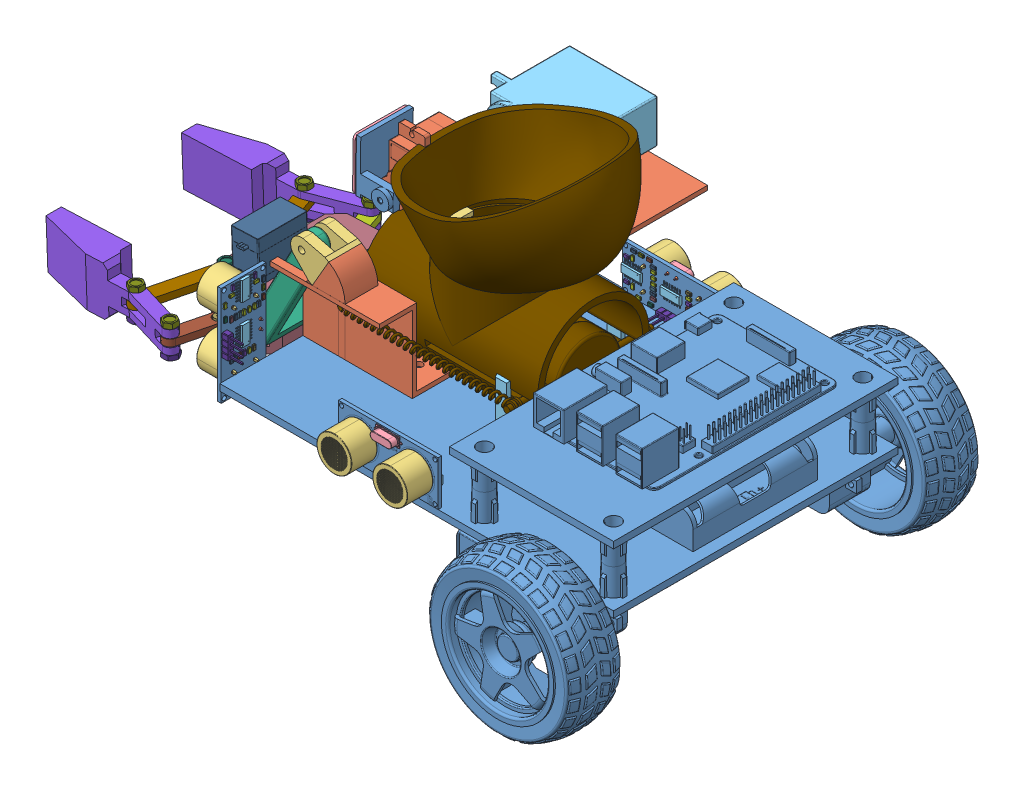
SolidWorks assembly Final1, configuration Default. Lengths in mm.
Overall size (322.81 176.18 188.6).
225 component instances, 41 part files, 17 mates.
Components (placement in the parent):
- body-final(18x13)-1: body-final(18x13) [Default] at (34.2506 -12.1128 3.3037) size (190.78 93.48 188.6)
- Assem3-1: Assem3 [Default] at (112.861 101.0924 210.176) x (0 0 -1) z (-1 0 0) size (142.46 166.43 202.05)
  - Base-1: Base [Default] at (127.5084 -19.7377 87.1974) size (130 49.99 70.01)
  - joint-1: joint [Default] at (35.8214 -26.2329 92.7019) x (0 -0.866025 -0.5) z (-1 0 0) size (15 15 15)
  - joint-half-1: joint-half [Default] at (97.1971 -26.2329 92.7019) x (0 0.866025 0.5) z (1 0 0) size (15 15 15)
  - Servo MG996R-1: Servo MG996R [Predeterminado] at (153.349 -21.2329 111.3621) x (0 0 -1) z (0 1 0) size (53.6 47.6 20)
  - arm1-1: arm1 [Default] at (128.0479 7.6553 52.8151) x (1 0 0) z (0 -0.885193 -0.465225) size (110.02 107.88 131.32)
    - arm-2: arm [Default] at (-24.8916 55.9585 30.1716) size (87 10 66.93)
    - Assembly 2.0 upload.stp-2: Assembly 2.0 upload.stp [Default] at (-62.3508 78.3564 -62.8111) x (0 -0.866025 0.5) z (-1 0 0) size (99.56 43.3 110.02)
      - gear.stp-1: gear.stp [Default] at (1.3043 -4.9957 -15) x (0.330984 0 0.943636) z (-0.943636 0 0.330984) size (53 3 32)
      - gripper.stp-1: gripper.stp [Default] at (-7.3079 -8.4957 47.6327) size (71 22 21.5)
      - tuas.stp-1: tuas.stp [Default] at (-30.3079 -1.9957 40.1327) x (-0.966894 0 -0.255178) z (-0.255178 0 0.966894) size (6.5 3 40.25)
      - gripper.stp-2: gripper.stp [Default] at (-9.8664 1.0043 -46.8477) x (1 0 0) z (0 0 -1) size (71 22 21.5)
      - tuas.stp-2: tuas.stp [Default] at (-32.8664 -1.9957 -39.3477) x (0.943636 0 -0.330984) z (-0.330984 0 -0.943636) size (6.5 3 40.25)
      - microservoSG90.stp-1: microservoSG90.stp [Default] at (1.3043 28.3043 9.9) x (0 0 -1) z (-1 0 0) size (32.3 29.8 12.41)
      - gear 2.1.stp-1: gear 2.1.stp [Default] at (1.3043 -1.9957 15) x (0.255178 0 -0.966894) z (-0.966894 0 -0.255178) size (52.85 3 31.7)
      - servo horn 1 v2.stp-1: servo horn 1 v2.stp [Default] at (1.3043 -1.4957 15) x (-0.966894 0 -0.255178) z (-0.255178 0 0.966894) size (7.2 3.7 21.2)
      - base 2.0 upload.stp-1: base 2.0 upload.stp [Default] at (28.3043 -7.9957 35) size (50 18.1 60)
      - Gear Ring.stp-1: Gear Ring.stp [Default] at (1.3043 -1.7957 -15) x (-0.620589 0 -0.784136) z (0.784136 0 -0.620589) size (18 2 18)
      - AS 1427 - M3 x 10.stp-1: AS 1427 - M3 x 10.stp [Default] at (1.3043 0.2043 -15) x (0 -1 0) z (0 0 1) size (12.33 5.5 6.35)
      - AS 1427 - M3 x 10.stp-2: AS 1427 - M3 x 10.stp [Default] at (-21.6957 -1.9957 -7.5) x (0 -1 0) z (0 0 1) size (12.33 5.5 6.35)
      - AS 1427 - M3 x 10.stp-3: AS 1427 - M3 x 10.stp [Default] at (-21.6957 -1.9957 7.5) x (0 -1 0) z (0 0 1) size (12.33 5.5 6.35)
      - AS 1427 - M3 x 12.stp-1: AS 1427 - M3 x 12.stp [Default] at (-9.8664 1.0043 -46.8477) x (0 -1 0) z (0 0 1) size (14.33 5.5 6.35)
      - AS 1427 - M3 x 12.stp-2: AS 1427 - M3 x 12.stp [Default] at (-32.8664 1.0043 -39.3477) x (0 -1 0) z (0 0 1) size (14.33 5.5 6.35)
      - AS 1427 - M3 x 12.stp-3: AS 1427 - M3 x 12.stp [Default] at (-7.3079 1.5043 47.6327) x (0 -1 0) z (0 0 1) size (14.33 5.5 6.35)
      - AS 1427 - M3 x 12.stp-4: AS 1427 - M3 x 12.stp [Default] at (-30.3079 1.5043 40.1327) x (0 -1 0) z (0 0 1) size (14.33 5.5 6.35)
      - AS 1112 - M3,5.stp-1: AS 1112 - M3,5.stp [Default] at (1.3043 -10.0957 -15) x (0 1 0) z (0 0 1) size (2.1 6.93 6)
      - AS 1112 - M3,5.stp-2: AS 1112 - M3,5.stp [Default] at (-21.6957 -10.0957 -7.5) x (0 1 0) z (0 0 1) size (2.1 6.93 6)
      - AS 1112 - M3,5.stp-3: AS 1112 - M3,5.stp [Default] at (-21.6957 -10.0957 7.5) x (0 1 0) z (0 0 1) size (2.1 6.93 6)
      - AS 1112 - M3,5.stp-4: AS 1112 - M3,5.stp [Default] at (-32.8664 -11.0957 -39.3477) x (0 1 0) z (0 0 1) size (2.1 6.93 6)
      - AS 1112 - M3,5.stp-5: AS 1112 - M3,5.stp [Default] at (-9.8664 -11.0957 -46.8477) x (0 1 0) z (0 0 1) size (2.1 6.93 6)
      - AS 1112 - M3,5.stp-6: AS 1112 - M3,5.stp [Default] at (-30.3079 -10.5957 40.1327) x (0 1 0) z (0 0 1) size (2.1 6.93 6)
      - AS 1112 - M3,5.stp-7: AS 1112 - M3,5.stp [Default] at (-7.3079 -10.5957 47.6327) x (0 1 0) z (0 0 1) size (2.1 6.93 6)
      - ISO 7046-1 - M1,6 x 8 - 4.8 - H.stp-1: ISO 7046-1 - M1,6 x 8 - 4.8 - H.stp [Default] at (1.3043 -5.9957 15) x (0 1 0) z (0 0 1) size (8 3 3)
- HC-SR04.STEP-1: HC-SR04.STEP [Default] at (-2.8752 98.1933 88.4487) x (0 1 0) z (0 0 1) size (45.5 21.95 20.5)
  - HC-SR04board.STEP-1: HC-SR04board.STEP [Default] at origin size (45.5 1.61 20.5)
  - solder.STEP-1: solder.STEP [Default] at (-3.8014 1.6 8.5727) size (1.17 0.65 1.17)
  - solder.STEP-2: solder.STEP [Default] at (-1.2614 1.6 8.5727) size (1.17 0.65 1.17)
  - solder.STEP-3: solder.STEP [Default] at (1.2786 1.6 8.5727) size (1.17 0.65 1.17)
  - solder.STEP-4: solder.STEP [Default] at (3.8186 1.6 8.5727) size (1.17 0.65 1.17)
  - Emitter.STEP-1: Emitter.STEP [Default] at (-12.75 1.6 0) size (15.9 15.2 15.9)
  - Emitter.STEP-2: Emitter.STEP [Default] at (12.75 1.6 0) size (15.9 15.2 15.9)
  - CrystalOscillator.STEP-1: CrystalOscillator.STEP [Default] at (0 1.6 -7.5) size (13.3 6.4 4.5)
  - solder.STEP-5: solder.STEP [Default] at (-2.0167 0 -7.5286) x (-0.837169 0 -0.546944) z (-0.546944 0 0.837169) size (1.17 0.65 1.17)
  - solder.STEP-6: solder.STEP [Default] at (1.9833 0 -7.5286) x (-0.837169 0 -0.546944) z (-0.546944 0 0.837169) size (1.17 0.65 1.17)
  - smdChip14pin.STEP-1: smdChip14pin.STEP [Default] at (22.25 -0.725 0) x (0 0 -1) z (-1 0 0) size (7.3 1.22 8.75)
  - smdChip14pin.STEP-2: smdChip14pin.STEP [Default] at (4.375 -0.725 0) x (0 0 -1) z (-1 0 0) size (7.3 1.22 8.75)
  - smdChip16pin.STEP-1: smdChip16pin.STEP [Default] at (-18.6 -0.725 5) x (1 0 0) z (0 0 -1) size (7.3 1.22 10)
  - smdceramiccapacitor.STEP-1: smdceramiccapacitor.STEP [Default] at (17.8499 0 -5.5522) x (0 0 -1) z (-1 0 0) size (2.52 0.61 1.3)
  - smdceramiccapacitor.STEP-2: smdceramiccapacitor.STEP [Default] at (17.8499 0 5.585) x (0 0 -1) z (-1 0 0) size (2.52 0.61 1.3)
  - smdceramiccapacitor.STEP-3: smdceramiccapacitor.STEP [Default] at (15.2359 0 8.7006) x (-1 0 0) z (0 0 1) size (2.52 0.61 1.3)
  - smdceramiccapacitor.STEP-4: smdceramiccapacitor.STEP [Default] at (8.3844 0 0.0383) x (-1 0 0) z (0 0 1) size (2.52 0.61 1.3)
  - smdceramiccapacitor.STEP-5: smdceramiccapacitor.STEP [Default] at (8.3844 0 -4.7577) x (-1 0 0) z (0 0 1) size (2.52 0.61 1.3)
  - smdceramiccapacitor.STEP-6: smdceramiccapacitor.STEP [Default] at (8.3844 0 -2.3108) x (-1 0 0) z (0 0 1) size (2.52 0.61 1.3)
  - smdceramiccapacitor.STEP-7: smdceramiccapacitor.STEP [Default] at (-7.8145 0 -2.3108) x (-1 0 0) z (0 0 1) size (2.52 0.61 1.3)
  - smdResistor753.STEP-1: smdResistor753.STEP [Default] at (20.6199 0 5.0565) x (-1 0 0) z (0 0 1) size (2.53 0.63 1.31)
  - smdResistor753.STEP-2: smdResistor753.STEP [Default] at (-7.7732 0 -0.1429) x (-1 0 0) z (0 0 1) size (2.53 0.63 1.31)
  - smdResistor753.STEP-3: smdResistor753.STEP [Default] at (20.6199 0 -4.936) x (-1 0 0) z (0 0 1) size (2.53 0.63 1.31)
  - smdResistor392.STEP-1: smdResistor392.STEP [Default] at (-18.578 0 -6.4389) x (-1 0 0) z (0 0 1) size (2.53 0.63 1.31)
  - smdResistor103.STEP-1: smdResistor103.STEP [Default] at (-18.578 0 6.8031) x (-1 0 0) z (0 0 1) size (2.53 0.63 1.31)
  - smdResistor124.STEP-1: smdResistor124.STEP [Default] at (-7.7732 0 1.8639) x (-1 0 0) z (0 0 1) size (2.53 0.63 1.31)
  - smdResistor103.STEP-2: smdResistor103.STEP [Default] at (-7.7732 0 3.8148) x (-1 0 0) z (0 0 1) size (2.53 0.63 1.31)
  - smdResistor103.STEP-3: smdResistor103.STEP [Default] at (-7.7732 0 5.8773) x (-1 0 0) z (0 0 1) size (2.53 0.63 1.31)
  - smdResistor335.STEP-1: smdResistor335.STEP [Default] at (-7.7732 0 -4.435) x (-1 0 0) z (0 0 1) size (2.53 0.63 1.31)
  - smdResistor102.STEP-1: smdResistor102.STEP [Default] at (8.4383 0 5.8773) x (-1 0 0) z (0 0 1) size (2.53 0.63 1.31)
  - smdResistor103.STEP-4: smdResistor103.STEP [Default] at (8.4383 0 3.8148) x (-1 0 0) z (0 0 1) size (2.53 0.63 1.31)
  - smdResistor563.STEP-1: smdResistor563.STEP [Default] at (8.4383 0 1.8639) x (-1 0 0) z (0 0 1) size (2.53 0.63 1.31)
  - smdResistor103.STEP-5: smdResistor103.STEP [Default] at (8.4383 0 -6.6305) x (-1 0 0) z (0 0 1) size (2.53 0.63 1.31)
  - smdResistor622.STEP-1: smdResistor622.STEP [Default] at (9.6708 0 8.6421) x (-1 0 0) z (0 0 1) size (2.53 0.63 1.31)
  - smdResistor124.STEP-2: smdResistor124.STEP [Default] at (10.2038 0 -8.7291) x (-1 0 0) z (0 0 1) size (2.53 0.63 1.31)
  - smdResistor412.STEP-1: smdResistor412.STEP [Default] at (14.0013 0 -8.7291) x (-1 0 0) z (0 0 1) size (2.53 0.63 1.31)
  - smdResistor103.STEP-6: smdResistor103.STEP [Default] at (17.3324 0 -8.7291) x (-1 0 0) z (0 0 1) size (2.53 0.63 1.31)
  - solder.STEP-7: solder.STEP [Default] at (-12.8084 0 -5.0269) x (-0.837169 0 -0.546944) z (-0.546944 0 0.837169) size (1.17 0.65 1.17)
  - solder.STEP-8: solder.STEP [Default] at (-12.8084 0 5.0295) x (-0.837169 0 -0.546944) z (-0.546944 0 0.837169) size (1.17 0.65 1.17)
  - solder.STEP-9: solder.STEP [Default] at (12.7872 0 5.0295) x (-0.837169 0 -0.546944) z (-0.546944 0 0.837169) size (1.17 0.65 1.17)
  - solder.STEP-10: solder.STEP [Default] at (12.7872 0 -5.0269) x (-0.837169 0 -0.546944) z (-0.546944 0 0.837169) size (1.17 0.65 1.17)
  - headerMale.STEP-1: headerMale.STEP [Default] at (3.81 0 8.58) x (-1 0 0) z (0 0 1) size (2.54 11.1 2.54)
  - headerMale.STEP-2: headerMale.STEP [Default] at (1.27 0 8.58) x (-1 0 0) z (0 0 1) size (2.54 11.1 2.54)
  - headerMale.STEP-3: headerMale.STEP [Default] at (-1.27 0 8.58) x (-1 0 0) z (0 0 1) size (2.54 11.1 2.54)
  - headerMale.STEP-4: headerMale.STEP [Default] at (-3.81 0 8.58) x (-1 0 0) z (0 0 1) size (2.54 11.1 2.54)
- HC-SR04.STEP-2: HC-SR04.STEP [Default] at (75.5969 94.0802 83.9667) x (-1 0 0) z (0 -1 0) size (45.5 21.95 20.5)
  - HC-SR04board.STEP-1: HC-SR04board.STEP [Default] at origin size (45.5 1.61 20.5)
  - solder.STEP-1: solder.STEP [Default] at (-3.8014 1.6 8.5727) size (1.17 0.65 1.17)
  - solder.STEP-2: solder.STEP [Default] at (-1.2614 1.6 8.5727) size (1.17 0.65 1.17)
  - solder.STEP-3: solder.STEP [Default] at (1.2786 1.6 8.5727) size (1.17 0.65 1.17)
  - solder.STEP-4: solder.STEP [Default] at (3.8186 1.6 8.5727) size (1.17 0.65 1.17)
  - Emitter.STEP-1: Emitter.STEP [Default] at (-12.75 1.6 0) size (15.9 15.2 15.9)
  - Emitter.STEP-2: Emitter.STEP [Default] at (12.75 1.6 0) size (15.9 15.2 15.9)
  - CrystalOscillator.STEP-1: CrystalOscillator.STEP [Default] at (0 1.6 -7.5) size (13.3 6.4 4.5)
  - solder.STEP-5: solder.STEP [Default] at (-2.0167 0 -7.5286) x (-0.837169 0 -0.546944) z (-0.546944 0 0.837169) size (1.17 0.65 1.17)
  - solder.STEP-6: solder.STEP [Default] at (1.9833 0 -7.5286) x (-0.837169 0 -0.546944) z (-0.546944 0 0.837169) size (1.17 0.65 1.17)
  - smdChip14pin.STEP-1: smdChip14pin.STEP [Default] at (22.25 -0.725 0) x (0 0 -1) z (-1 0 0) size (7.3 1.22 8.75)
  - smdChip14pin.STEP-2: smdChip14pin.STEP [Default] at (4.375 -0.725 0) x (0 0 -1) z (-1 0 0) size (7.3 1.22 8.75)
  - smdChip16pin.STEP-1: smdChip16pin.STEP [Default] at (-18.6 -0.725 5) x (1 0 0) z (0 0 -1) size (7.3 1.22 10)
  - smdceramiccapacitor.STEP-1: smdceramiccapacitor.STEP [Default] at (17.8499 0 -5.5522) x (0 0 -1) z (-1 0 0) size (2.52 0.61 1.3)
  - smdceramiccapacitor.STEP-2: smdceramiccapacitor.STEP [Default] at (17.8499 0 5.585) x (0 0 -1) z (-1 0 0) size (2.52 0.61 1.3)
  - smdceramiccapacitor.STEP-3: smdceramiccapacitor.STEP [Default] at (15.2359 0 8.7006) x (-1 0 0) z (0 0 1) size (2.52 0.61 1.3)
  - smdceramiccapacitor.STEP-4: smdceramiccapacitor.STEP [Default] at (8.3844 0 0.0383) x (-1 0 0) z (0 0 1) size (2.52 0.61 1.3)
  - smdceramiccapacitor.STEP-5: smdceramiccapacitor.STEP [Default] at (8.3844 0 -4.7577) x (-1 0 0) z (0 0 1) size (2.52 0.61 1.3)
  - smdceramiccapacitor.STEP-6: smdceramiccapacitor.STEP [Default] at (8.3844 0 -2.3108) x (-1 0 0) z (0 0 1) size (2.52 0.61 1.3)
  - smdceramiccapacitor.STEP-7: smdceramiccapacitor.STEP [Default] at (-7.8145 0 -2.3108) x (-1 0 0) z (0 0 1) size (2.52 0.61 1.3)
  - smdResistor753.STEP-1: smdResistor753.STEP [Default] at (20.6199 0 5.0565) x (-1 0 0) z (0 0 1) size (2.53 0.63 1.31)
  - smdResistor753.STEP-2: smdResistor753.STEP [Default] at (-7.7732 0 -0.1429) x (-1 0 0) z (0 0 1) size (2.53 0.63 1.31)
  - smdResistor753.STEP-3: smdResistor753.STEP [Default] at (20.6199 0 -4.936) x (-1 0 0) z (0 0 1) size (2.53 0.63 1.31)
  - smdResistor392.STEP-1: smdResistor392.STEP [Default] at (-18.578 0 -6.4389) x (-1 0 0) z (0 0 1) size (2.53 0.63 1.31)
  - smdResistor103.STEP-1: smdResistor103.STEP [Default] at (-18.578 0 6.8031) x (-1 0 0) z (0 0 1) size (2.53 0.63 1.31)
  - smdResistor124.STEP-1: smdResistor124.STEP [Default] at (-7.7732 0 1.8639) x (-1 0 0) z (0 0 1) size (2.53 0.63 1.31)
  - smdResistor103.STEP-2: smdResistor103.STEP [Default] at (-7.7732 0 3.8148) x (-1 0 0) z (0 0 1) size (2.53 0.63 1.31)
  - smdResistor103.STEP-3: smdResistor103.STEP [Default] at (-7.7732 0 5.8773) x (-1 0 0) z (0 0 1) size (2.53 0.63 1.31)
  - smdResistor335.STEP-1: smdResistor335.STEP [Default] at (-7.7732 0 -4.435) x (-1 0 0) z (0 0 1) size (2.53 0.63 1.31)
  - smdResistor102.STEP-1: smdResistor102.STEP [Default] at (8.4383 0 5.8773) x (-1 0 0) z (0 0 1) size (2.53 0.63 1.31)
  - smdResistor103.STEP-4: smdResistor103.STEP [Default] at (8.4383 0 3.8148) x (-1 0 0) z (0 0 1) size (2.53 0.63 1.31)
  - smdResistor563.STEP-1: smdResistor563.STEP [Default] at (8.4383 0 1.8639) x (-1 0 0) z (0 0 1) size (2.53 0.63 1.31)
  - smdResistor103.STEP-5: smdResistor103.STEP [Default] at (8.4383 0 -6.6305) x (-1 0 0) z (0 0 1) size (2.53 0.63 1.31)
  - smdResistor622.STEP-1: smdResistor622.STEP [Default] at (9.6708 0 8.6421) x (-1 0 0) z (0 0 1) size (2.53 0.63 1.31)
  - smdResistor124.STEP-2: smdResistor124.STEP [Default] at (10.2038 0 -8.7291) x (-1 0 0) z (0 0 1) size (2.53 0.63 1.31)
  - smdResistor412.STEP-1: smdResistor412.STEP [Default] at (14.0013 0 -8.7291) x (-1 0 0) z (0 0 1) size (2.53 0.63 1.31)
  - smdResistor103.STEP-6: smdResistor103.STEP [Default] at (17.3324 0 -8.7291) x (-1 0 0) z (0 0 1) size (2.53 0.63 1.31)
  - solder.STEP-7: solder.STEP [Default] at (-12.8084 0 -5.0269) x (-0.837169 0 -0.546944) z (-0.546944 0 0.837169) size (1.17 0.65 1.17)
  - solder.STEP-8: solder.STEP [Default] at (-12.8084 0 5.0295) x (-0.837169 0 -0.546944) z (-0.546944 0 0.837169) size (1.17 0.65 1.17)
  - solder.STEP-9: solder.STEP [Default] at (12.7872 0 5.0295) x (-0.837169 0 -0.546944) z (-0.546944 0 0.837169) size (1.17 0.65 1.17)
  - solder.STEP-10: solder.STEP [Default] at (12.7872 0 -5.0269) x (-0.837169 0 -0.546944) z (-0.546944 0 0.837169) size (1.17 0.65 1.17)
  - headerMale.STEP-1: headerMale.STEP [Default] at (3.81 0 8.58) x (-1 0 0) z (0 0 1) size (2.54 11.1 2.54)
  - headerMale.STEP-2: headerMale.STEP [Default] at (1.27 0 8.58) x (-1 0 0) z (0 0 1) size (2.54 11.1 2.54)
  - headerMale.STEP-3: headerMale.STEP [Default] at (-1.27 0 8.58) x (-1 0 0) z (0 0 1) size (2.54 11.1 2.54)
  - headerMale.STEP-4: headerMale.STEP [Default] at (-3.81 0 8.58) x (-1 0 0) z (0 0 1) size (2.54 11.1 2.54)
- HC-SR04.STEP-3: HC-SR04.STEP [Default] at (74.1405 94.0802 210.7667) x (1 0 0) z (0 -1 0) size (45.5 21.95 20.5)
  - HC-SR04board.STEP-1: HC-SR04board.STEP [Default] at origin size (45.5 1.61 20.5)
  - solder.STEP-1: solder.STEP [Default] at (-3.8014 1.6 8.5727) size (1.17 0.65 1.17)
  - solder.STEP-2: solder.STEP [Default] at (-1.2614 1.6 8.5727) size (1.17 0.65 1.17)
  - solder.STEP-3: solder.STEP [Default] at (1.2786 1.6 8.5727) size (1.17 0.65 1.17)
  - solder.STEP-4: solder.STEP [Default] at (3.8186 1.6 8.5727) size (1.17 0.65 1.17)
  - Emitter.STEP-1: Emitter.STEP [Default] at (-12.75 1.6 0) size (15.9 15.2 15.9)
  - Emitter.STEP-2: Emitter.STEP [Default] at (12.75 1.6 0) size (15.9 15.2 15.9)
  - CrystalOscillator.STEP-1: CrystalOscillator.STEP [Default] at (0 1.6 -7.5) size (13.3 6.4 4.5)
  - solder.STEP-5: solder.STEP [Default] at (-2.0167 0 -7.5286) x (-0.837169 0 -0.546944) z (-0.546944 0 0.837169) size (1.17 0.65 1.17)
  - solder.STEP-6: solder.STEP [Default] at (1.9833 0 -7.5286) x (-0.837169 0 -0.546944) z (-0.546944 0 0.837169) size (1.17 0.65 1.17)
  - smdChip14pin.STEP-1: smdChip14pin.STEP [Default] at (22.25 -0.725 0) x (0 0 -1) z (-1 0 0) size (7.3 1.22 8.75)
  - smdChip14pin.STEP-2: smdChip14pin.STEP [Default] at (4.375 -0.725 0) x (0 0 -1) z (-1 0 0) size (7.3 1.22 8.75)
  - smdChip16pin.STEP-1: smdChip16pin.STEP [Default] at (-18.6 -0.725 5) x (1 0 0) z (0 0 -1) size (7.3 1.22 10)
  - smdceramiccapacitor.STEP-1: smdceramiccapacitor.STEP [Default] at (17.8499 0 -5.5522) x (0 0 -1) z (-1 0 0) size (2.52 0.61 1.3)
  - smdceramiccapacitor.STEP-2: smdceramiccapacitor.STEP [Default] at (17.8499 0 5.585) x (0 0 -1) z (-1 0 0) size (2.52 0.61 1.3)
  - smdceramiccapacitor.STEP-3: smdceramiccapacitor.STEP [Default] at (15.2359 0 8.7006) x (-1 0 0) z (0 0 1) size (2.52 0.61 1.3)
  - smdceramiccapacitor.STEP-4: smdceramiccapacitor.STEP [Default] at (8.3844 0 0.0383) x (-1 0 0) z (0 0 1) size (2.52 0.61 1.3)
  - smdceramiccapacitor.STEP-5: smdceramiccapacitor.STEP [Default] at (8.3844 0 -4.7577) x (-1 0 0) z (0 0 1) size (2.52 0.61 1.3)
  - smdceramiccapacitor.STEP-6: smdceramiccapacitor.STEP [Default] at (8.3844 0 -2.3108) x (-1 0 0) z (0 0 1) size (2.52 0.61 1.3)
  - smdceramiccapacitor.STEP-7: smdceramiccapacitor.STEP [Default] at (-7.8145 0 -2.3108) x (-1 0 0) z (0 0 1) size (2.52 0.61 1.3)
  - smdResistor753.STEP-1: smdResistor753.STEP [Default] at (20.6199 0 5.0565) x (-1 0 0) z (0 0 1) size (2.53 0.63 1.31)
  - smdResistor753.STEP-2: smdResistor753.STEP [Default] at (-7.7732 0 -0.1429) x (-1 0 0) z (0 0 1) size (2.53 0.63 1.31)
  - smdResistor753.STEP-3: smdResistor753.STEP [Default] at (20.6199 0 -4.936) x (-1 0 0) z (0 0 1) size (2.53 0.63 1.31)
  - smdResistor392.STEP-1: smdResistor392.STEP [Default] at (-18.578 0 -6.4389) x (-1 0 0) z (0 0 1) size (2.53 0.63 1.31)
  - smdResistor103.STEP-1: smdResistor103.STEP [Default] at (-18.578 0 6.8031) x (-1 0 0) z (0 0 1) size (2.53 0.63 1.31)
  - smdResistor124.STEP-1: smdResistor124.STEP [Default] at (-7.7732 0 1.8639) x (-1 0 0) z (0 0 1) size (2.53 0.63 1.31)
  - smdResistor103.STEP-2: smdResistor103.STEP [Default] at (-7.7732 0 3.8148) x (-1 0 0) z (0 0 1) size (2.53 0.63 1.31)
  - smdResistor103.STEP-3: smdResistor103.STEP [Default] at (-7.7732 0 5.8773) x (-1 0 0) z (0 0 1) size (2.53 0.63 1.31)
  - smdResistor335.STEP-1: smdResistor335.STEP [Default] at (-7.7732 0 -4.435) x (-1 0 0) z (0 0 1) size (2.53 0.63 1.31)
  - smdResistor102.STEP-1: smdResistor102.STEP [Default] at (8.4383 0 5.8773) x (-1 0 0) z (0 0 1) size (2.53 0.63 1.31)
  - smdResistor103.STEP-4: smdResistor103.STEP [Default] at (8.4383 0 3.8148) x (-1 0 0) z (0 0 1) size (2.53 0.63 1.31)
  - smdResistor563.STEP-1: smdResistor563.STEP [Default] at (8.4383 0 1.8639) x (-1 0 0) z (0 0 1) size (2.53 0.63 1.31)
  - smdResistor103.STEP-5: smdResistor103.STEP [Default] at (8.4383 0 -6.6305) x (-1 0 0) z (0 0 1) size (2.53 0.63 1.31)
  - smdResistor622.STEP-1: smdResistor622.STEP [Default] at (9.6708 0 8.6421) x (-1 0 0) z (0 0 1) size (2.53 0.63 1.31)
  - smdResistor124.STEP-2: smdResistor124.STEP [Default] at (10.2038 0 -8.7291) x (-1 0 0) z (0 0 1) size (2.53 0.63 1.31)
  - smdResistor412.STEP-1: smdResistor412.STEP [Default] at (14.0013 0 -8.7291) x (-1 0 0) z (0 0 1) size (2.53 0.63 1.31)
  - smdResistor103.STEP-6: smdResistor103.STEP [Default] at (17.3324 0 -8.7291) x (-1 0 0) z (0 0 1) size (2.53 0.63 1.31)
  - solder.STEP-7: solder.STEP [Default] at (-12.8084 0 -5.0269) x (-0.837169 0 -0.546944) z (-0.546944 0 0.837169) size (1.17 0.65 1.17)
  - solder.STEP-8: solder.STEP [Default] at (-12.8084 0 5.0295) x (-0.837169 0 -0.546944) z (-0.546944 0 0.837169) size (1.17 0.65 1.17)
  - solder.STEP-9: solder.STEP [Default] at (12.7872 0 5.0295) x (-0.837169 0 -0.546944) z (-0.546944 0 0.837169) size (1.17 0.65 1.17)
  - solder.STEP-10: solder.STEP [Default] at (12.7872 0 -5.0269) x (-0.837169 0 -0.546944) z (-0.546944 0 0.837169) size (1.17 0.65 1.17)
  - headerMale.STEP-1: headerMale.STEP [Default] at (3.81 0 8.58) x (-1 0 0) z (0 0 1) size (2.54 11.1 2.54)
  - headerMale.STEP-2: headerMale.STEP [Default] at (1.27 0 8.58) x (-1 0 0) z (0 0 1) size (2.54 11.1 2.54)
  - headerMale.STEP-3: headerMale.STEP [Default] at (-1.27 0 8.58) x (-1 0 0) z (0 0 1) size (2.54 11.1 2.54)
  - headerMale.STEP-4: headerMale.STEP [Default] at (-3.81 0 8.58) x (-1 0 0) z (0 0 1) size (2.54 11.1 2.54)
- HC-SR04.STEP-4: HC-SR04.STEP [Default] at (-2.8752 98.3778 201.4749) x (0 1 0) z (0 0 1) size (45.5 21.95 20.5)
  - HC-SR04board.STEP-1: HC-SR04board.STEP [Default] at origin size (45.5 1.61 20.5)
  - solder.STEP-1: solder.STEP [Default] at (-3.8014 1.6 8.5727) size (1.17 0.65 1.17)
  - solder.STEP-2: solder.STEP [Default] at (-1.2614 1.6 8.5727) size (1.17 0.65 1.17)
  - solder.STEP-3: solder.STEP [Default] at (1.2786 1.6 8.5727) size (1.17 0.65 1.17)
  - solder.STEP-4: solder.STEP [Default] at (3.8186 1.6 8.5727) size (1.17 0.65 1.17)
  - Emitter.STEP-1: Emitter.STEP [Default] at (-12.75 1.6 0) size (15.9 15.2 15.9)
  - Emitter.STEP-2: Emitter.STEP [Default] at (12.75 1.6 0) size (15.9 15.2 15.9)
  - CrystalOscillator.STEP-1: CrystalOscillator.STEP [Default] at (0 1.6 -7.5) size (13.3 6.4 4.5)
  - solder.STEP-5: solder.STEP [Default] at (-2.0167 0 -7.5286) x (-0.837169 0 -0.546944) z (-0.546944 0 0.837169) size (1.17 0.65 1.17)
  - solder.STEP-6: solder.STEP [Default] at (1.9833 0 -7.5286) x (-0.837169 0 -0.546944) z (-0.546944 0 0.837169) size (1.17 0.65 1.17)
  - smdChip14pin.STEP-1: smdChip14pin.STEP [Default] at (22.25 -0.725 0) x (0 0 -1) z (-1 0 0) size (7.3 1.22 8.75)
  - smdChip14pin.STEP-2: smdChip14pin.STEP [Default] at (4.375 -0.725 0) x (0 0 -1) z (-1 0 0) size (7.3 1.22 8.75)
  - smdChip16pin.STEP-1: smdChip16pin.STEP [Default] at (-18.6 -0.725 5) x (1 0 0) z (0 0 -1) size (7.3 1.22 10)
  - smdceramiccapacitor.STEP-1: smdceramiccapacitor.STEP [Default] at (17.8499 0 -5.5522) x (0 0 -1) z (-1 0 0) size (2.52 0.61 1.3)
  - smdceramiccapacitor.STEP-2: smdceramiccapacitor.STEP [Default] at (17.8499 0 5.585) x (0 0 -1) z (-1 0 0) size (2.52 0.61 1.3)
  - smdceramiccapacitor.STEP-3: smdceramiccapacitor.STEP [Default] at (15.2359 0 8.7006) x (-1 0 0) z (0 0 1) size (2.52 0.61 1.3)
  - smdceramiccapacitor.STEP-4: smdceramiccapacitor.STEP [Default] at (8.3844 0 0.0383) x (-1 0 0) z (0 0 1) size (2.52 0.61 1.3)
  - smdceramiccapacitor.STEP-5: smdceramiccapacitor.STEP [Default] at (8.3844 0 -4.7577) x (-1 0 0) z (0 0 1) size (2.52 0.61 1.3)
  - smdceramiccapacitor.STEP-6: smdceramiccapacitor.STEP [Default] at (8.3844 0 -2.3108) x (-1 0 0) z (0 0 1) size (2.52 0.61 1.3)
  - smdceramiccapacitor.STEP-7: smdceramiccapacitor.STEP [Default] at (-7.8145 0 -2.3108) x (-1 0 0) z (0 0 1) size (2.52 0.61 1.3)
  - smdResistor753.STEP-1: smdResistor753.STEP [Default] at (20.6199 0 5.0565) x (-1 0 0) z (0 0 1) size (2.53 0.63 1.31)
  - smdResistor753.STEP-2: smdResistor753.STEP [Default] at (-7.7732 0 -0.1429) x (-1 0 0) z (0 0 1) size (2.53 0.63 1.31)
  - smdResistor753.STEP-3: smdResistor753.STEP [Default] at (20.6199 0 -4.936) x (-1 0 0) z (0 0 1) size (2.53 0.63 1.31)
  - smdResistor392.STEP-1: smdResistor392.STEP [Default] at (-18.578 0 -6.4389) x (-1 0 0) z (0 0 1) size (2.53 0.63 1.31)
  - smdResistor103.STEP-1: smdResistor103.STEP [Default] at (-18.578 0 6.8031) x (-1 0 0) z (0 0 1) size (2.53 0.63 1.31)
  - smdResistor124.STEP-1: smdResistor124.STEP [Default] at (-7.7732 0 1.8639) x (-1 0 0) z (0 0 1) size (2.53 0.63 1.31)
  - smdResistor103.STEP-2: smdResistor103.STEP [Default] at (-7.7732 0 3.8148) x (-1 0 0) z (0 0 1) size (2.53 0.63 1.31)
  - smdResistor103.STEP-3: smdResistor103.STEP [Default] at (-7.7732 0 5.8773) x (-1 0 0) z (0 0 1) size (2.53 0.63 1.31)
  - smdResistor335.STEP-1: smdResistor335.STEP [Default] at (-7.7732 0 -4.435) x (-1 0 0) z (0 0 1) size (2.53 0.63 1.31)
  - smdResistor102.STEP-1: smdResistor102.STEP [Default] at (8.4383 0 5.8773) x (-1 0 0) z (0 0 1) size (2.53 0.63 1.31)
  - smdResistor103.STEP-4: smdResistor103.STEP [Default] at (8.4383 0 3.8148) x (-1 0 0) z (0 0 1) size (2.53 0.63 1.31)
  - smdResistor563.STEP-1: smdResistor563.STEP [Default] at (8.4383 0 1.8639) x (-1 0 0) z (0 0 1) size (2.53 0.63 1.31)
  - smdResistor103.STEP-5: smdResistor103.STEP [Default] at (8.4383 0 -6.6305) x (-1 0 0) z (0 0 1) size (2.53 0.63 1.31)
  - smdResistor622.STEP-1: smdResistor622.STEP [Default] at (9.6708 0 8.6421) x (-1 0 0) z (0 0 1) size (2.53 0.63 1.31)
  - smdResistor124.STEP-2: smdResistor124.STEP [Default] at (10.2038 0 -8.7291) x (-1 0 0) z (0 0 1) size (2.53 0.63 1.31)
  - smdResistor412.STEP-1: smdResistor412.STEP [Default] at (14.0013 0 -8.7291) x (-1 0 0) z (0 0 1) size (2.53 0.63 1.31)
  - smdResistor103.STEP-6: smdResistor103.STEP [Default] at (17.3324 0 -8.7291) x (-1 0 0) z (0 0 1) size (2.53 0.63 1.31)
  - solder.STEP-7: solder.STEP [Default] at (-12.8084 0 -5.0269) x (-0.837169 0 -0.546944) z (-0.546944 0 0.837169) size (1.17 0.65 1.17)
  - solder.STEP-8: solder.STEP [Default] at (-12.8084 0 5.0295) x (-0.837169 0 -0.546944) z (-0.546944 0 0.837169) size (1.17 0.65 1.17)
  - solder.STEP-9: solder.STEP [Default] at (12.7872 0 5.0295) x (-0.837169 0 -0.546944) z (-0.546944 0 0.837169) size (1.17 0.65 1.17)
  - solder.STEP-10: solder.STEP [Default] at (12.7872 0 -5.0269) x (-0.837169 0 -0.546944) z (-0.546944 0 0.837169) size (1.17 0.65 1.17)
  - headerMale.STEP-1: headerMale.STEP [Default] at (3.81 0 8.58) x (-1 0 0) z (0 0 1) size (2.54 11.1 2.54)
  - headerMale.STEP-2: headerMale.STEP [Default] at (1.27 0 8.58) x (-1 0 0) z (0 0 1) size (2.54 11.1 2.54)
  - headerMale.STEP-3: headerMale.STEP [Default] at (-1.27 0 8.58) x (-1 0 0) z (0 0 1) size (2.54 11.1 2.54)
  - headerMale.STEP-4: headerMale.STEP [Default] at (-3.81 0 8.58) x (-1 0 0) z (0 0 1) size (2.54 11.1 2.54)
- spring assembly to the cylinder_11.06pm-3: spring assembly to the cylinder_11.06pm [Default] at (-9.5913 59.4613 163.3267) x (0 -0.006839 -0.999977) z (1 0 0) size (91.01 106.15 98.97)
- cam module-1: cam module [Default] at (33.7733 184.3421 132.6049) x (0.932968 0.012728 0.359735) z (-0.070664 -0.973452 0.217709) size (30.45 42.9 38.46)
  - cam mount-1: cam mount [Default] at (-17.7592 5.162 32.7233) x (-0.359813 -0.908842 -0.211046) z (-0.013323 -0.221168 0.975145) size (26 17 24)
  - SG90 - Micro Servo 9g - Tower Pro.1-2: SG90 - Micro Servo 9g - Tower Pro.1 [Peça] at (-2.7343 7.8951 33.4722) x (0.013323 0.221168 -0.975145) z (0.932929 -0.353682 -0.067471) size (32.1 29.95 12.4)
  - cam base-2: cam base [Default] at (-10.6563 -6.0433 46.8268) x (-0.359813 -0.908842 -0.211046) z (0.932968 -0.352955 -0.070664) size (10 4.7 22)
- Cam V2.1 v1-2: Cam V2.1 v1 [Default] at (13.0748 154.9749 153.9942) x (-0.999995 0.003275 -0.000022) z (0 -0.006839 -0.999977) size (6.48 24.01 25.01)
- Lock-1: Lock [Default] at (28.7683 95.0031 148.0642) x (0 -0.127737 0.991808) z (1 0 0) size (64.66 48.3 50.53)
Mates (geometry in assembly coordinates):
- Coincident1: coincident anti-aligned: plane of body-final(18x13)-1 through (-2.8752 83.8302 212.3667) normal (0 1 0); plane of Assem3-1/Base-1 through (25.6636 83.8302 82.6676) normal (0 -1 0)
- Coincident3: coincident anti-aligned: line of body-final(18x13)-1 through (-2.8752 83.8302 82.3667) axis (0 0 1); line of Assem3-1/Base-1 through (-2.8752 83.8302 174.3667) axis (0 0 -1)
- Distance1: distance = 38 mm: line of body-final(18x13)-1 through (127.7248 83.8302 82.3667) axis (-1 0 0); line of Assem3-1/Base-1 through (-2.8752 83.8302 120.3667) axis (1 0 0)
- Coincident6: coincident aligned: line of body-final(18x13)-1 through (-2.8752 83.8302 212.3667) axis (1 0 0); line of HC-SR04.STEP-3/HC-SR04board.STEP-1 through (51.3905 83.8302 212.3667) axis (1 0 0)
- Coincident7: coincident anti-aligned: plane of body-final(18x13)-1 through (-2.8752 83.8302 212.3667) normal (0 1 0); plane of HC-SR04.STEP-3/HC-SR04board.STEP-1 through (51.3905 83.8302 212.3667) normal (0 -1 0)
- Coincident8: coincident aligned: line of body-final(18x13)-1 through (127.7248 83.8302 82.3667) axis (-1 0 0); line of HC-SR04.STEP-2/HC-SR04board.STEP-1 through (98.3469 83.8302 82.3667) axis (-1 0 0)
- Coincident9: coincident anti-aligned: plane of body-final(18x13)-1 through (-2.8752 83.8302 212.3667) normal (0 1 0); plane of HC-SR04.STEP-2/HC-SR04board.STEP-1 through (98.3469 83.8302 82.3667) normal (0 -1 0)
- Coincident10: coincident anti-aligned: plane of body-final(18x13)-1 through (-2.8752 83.8302 212.3667) normal (-1 0 0); plane of HC-SR04.STEP-1/HC-SR04board.STEP-1 through (-2.8752 98.1933 88.4487) normal (1 0 0)
- Coincident11: coincident anti-aligned: plane of body-final(18x13)-1 through (-2.8752 83.8302 212.3667) normal (-1 0 0); plane of HC-SR04.STEP-4/HC-SR04board.STEP-1 through (-2.8752 98.3778 201.4749) normal (1 0 0)
- Tangent3: tangent anti-aligned: plane of Assem3-1/Base-1 through (25.6636 85.8302 82.6676) normal (0 1 0); cylinder of spring assembly to the cylinder_11.06pm-3 through (110.1248 111.3302 146.5103) axis (-1 0 0) radius 25.5
- Coincident14: coincident anti-aligned: plane of body-final(18x13)-1 through (102.1248 108.3222 82.3667) normal (-1 0 0); plane of spring assembly to the cylinder_11.06pm-3 through (102.1248 111.3302 146.5103) normal (1 0 0)
- Coincident15: coincident anti-aligned: line of spring assembly to the cylinder_11.06pm-3 through (20.1248 137.3638 151.3324) axis (0 -0.006839 -0.999977); line of cam module-1/cam base-2 through (20.1248 137.2954 141.3326) axis (0 0.006839 0.999977)
- Coincident16: coincident anti-aligned: plane of spring assembly to the cylinder_11.06pm-3 through (20.1248 137.3296 146.3325) normal (0 0.999977 -0.006839); plane of cam module-1/cam base-2 through (22.6554 137.2417 133.4831) normal (0 -0.999977 0.006839)
- Coincident17: coincident: point of spring assembly to the cylinder_11.06pm-3; unknown of cam module-1/cam base-2
- Coincident18: coincident anti-aligned: plane of cam module-1/cam mount-1 through (13.0702 153.4411 138.0239) normal (-0.999995 0.003275 -0.000022); plane of Cam V2.1 v1-2 through (13.0748 154.9749 153.9942) normal (0.999995 -0.003275 0.000022)
- Coincident19: coincident: line of cam module-1/cam mount-1 through (13.1141 166.8924 141.9032) axis (0 0.006839 0.999977); plane of Cam V2.1 v1-2 through (13.1141 167.0463 164.4119) normal (0.003275 0.999971 -0.006839)
- Coincident21: coincident anti-aligned: plane of body-final(18x13)-1 through (-2.8752 80.8302 212.3667) normal (0 -1 0); plane of Lock-1 through (47.5293 80.8302 174.3073) normal (0 1 0)
